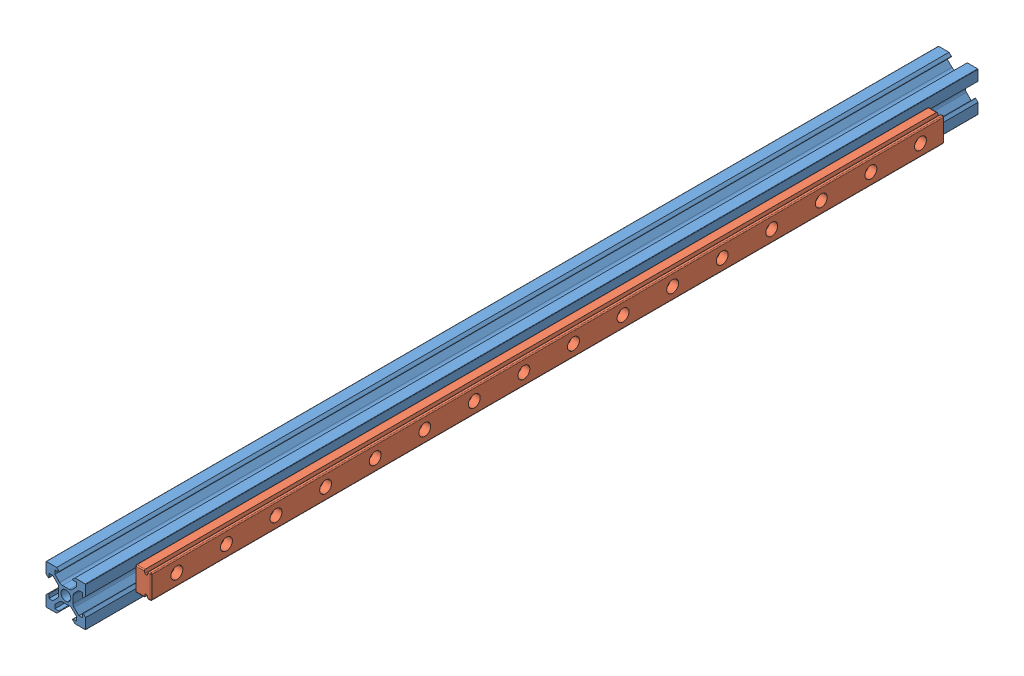
SolidWorks assembly Assem2, configuration Default. Lengths in mm.
Overall size (28 20 450).
2 component instances, 2 part files, 4 mates.
Components (placement in the parent):
- 20x20x450 VSlot-1: 20x20x450 VSlot [Valor predeterminado] at (161.9162 244.0373 117.3574) size (20 20 450)
- Rail 400mm-1: Rail 400mm [Default] at (175.9162 244.0373 542.3574) x (0 0 -1) z (1 0 0) size (400 12 8)
Mates (geometry in assembly coordinates):
- Coincident1: coincident: plane of 20x20x450 VSlot-1 through (171.9162 253.8373 567.3574) normal (1 0 0); plane of Rail 400mm-1 through (171.9162 250.0373 143.9311) normal (-1 0 0)
- Parallel1: parallel: plane of 20x20x450 VSlot-1 through (166.5162 254.0373 567.3574) normal (0 1 0); plane of Rail 400mm-1 through (176.4162 250.0373 143.9311) normal (0 1 0)
- Distance1: distance = 4 mm: plane of Rail 400mm-1 through (176.4162 250.0373 142.3574) normal (0 1 0); plane of 20x20x450 VSlot-1 through (166.5162 254.0373 567.3574) normal (0 1 0)
- Distance2: distance = 25 mm aligned: plane of Rail 400mm-1 through (175.9162 244.0373 542.3574) normal (0 0 1); plane of 20x20x450 VSlot-1 through (158.3334 235.3373 567.3574) normal (0 0 1)
